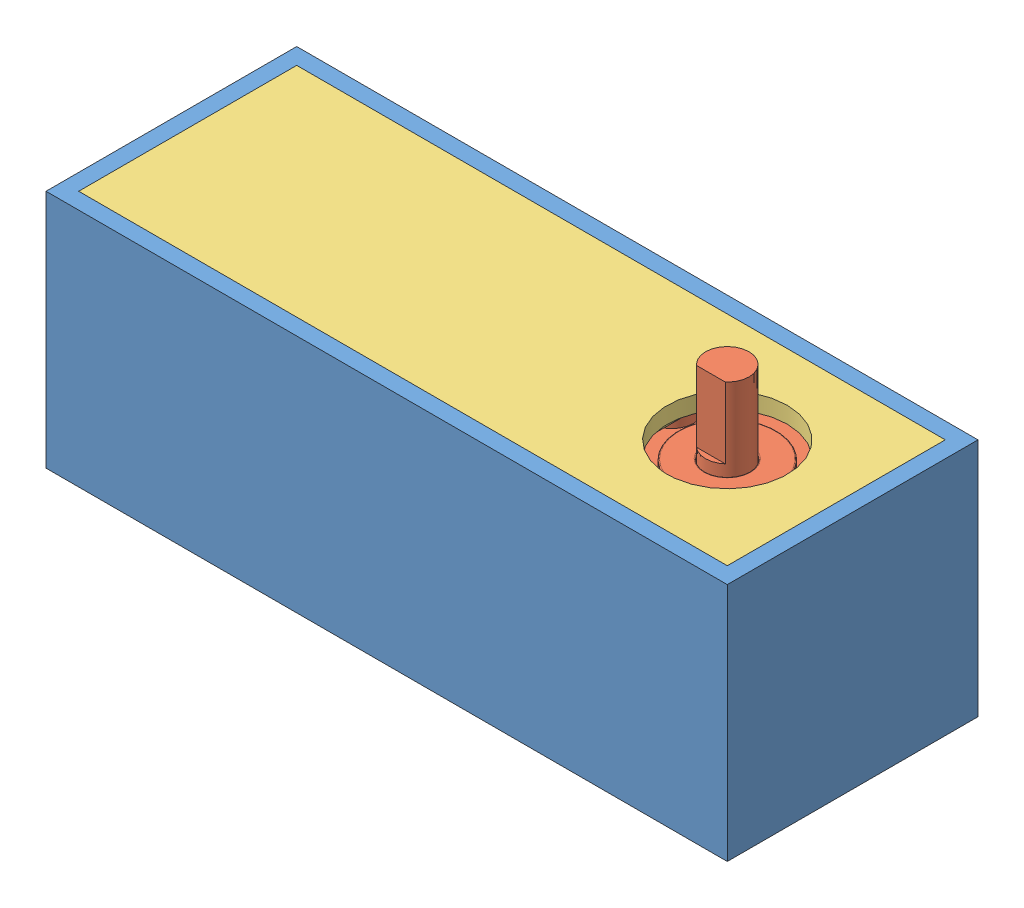
SolidWorks assembly Motor1WithCase, configuration Default. Lengths in mm.
Overall size (125 56 46).
3 component instances, 3 part files, 7 mates.
Components (placement in the parent):
- ArmBase-1: ArmBase [Default] at origin size (125 44 46)
- WormGearMotor-2: WormGearMotor [Default] at (-57.7 19.5 0) x (0 0 -1) z (0 -1 0) size (40 117.2 52)
- ArmBaseCover-2: ArmBaseCover [Default] at (0 44 0) x (-1 0 0) z (0 0 1) size (119 4.5 40)
Mates (geometry in assembly coordinates):
- Coincident4: coincident anti-aligned: plane of ArmBase-1 through (0 7 0) normal (0 1 0); plane of WormGearMotor-2 through (39.5 7 0) normal (0 -1 0)
- Coincident5: coincident anti-aligned: plane of ArmBase-1 through (59.5 44 -20) normal (0 0 1); plane of WormGearMotor-2 through (59.5 19.5 -20) normal (0 0 -1)
- Coincident6: coincident anti-aligned: plane of ArmBase-1 through (59.5 44 20) normal (-1 0 0); plane of WormGearMotor-2 through (59.5 19.5 0) normal (1 0 0)
- Coincident10: coincident anti-aligned: plane of WormGearMotor-2 through (50.5 39.5 14) normal (0 1 0); plane of ArmBaseCover-2 through (0 39.5 0) normal (0 -1 0)
- Coincident11: coincident anti-aligned: plane of ArmBase-1 through (59.5 44 -20) normal (0 0 1); plane of ArmBaseCover-2 through (59.5 41 -20) normal (0 0 -1)
- Coincident12: coincident anti-aligned: plane of ArmBase-1 through (-59.5 44 20) normal (1 0 0); plane of ArmBaseCover-2 through (-59.5 41 20) normal (-1 0 0)
- Coincident13: coordinate: point of ArmBase-1
